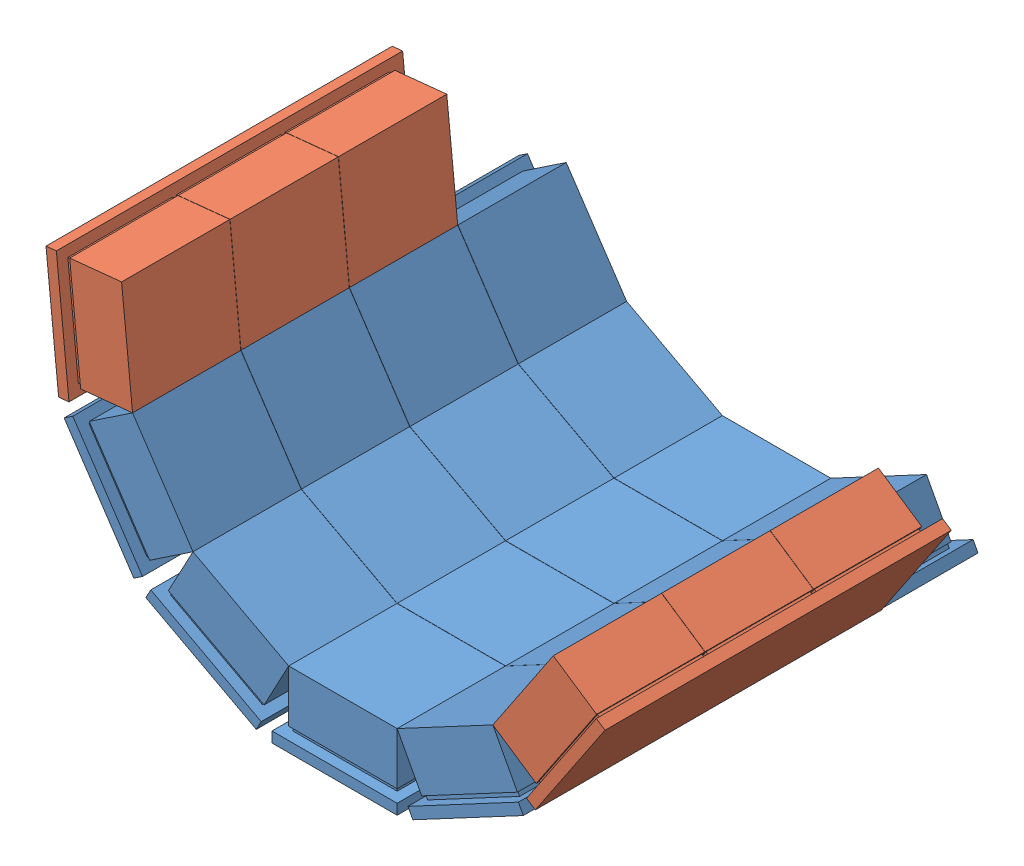
SolidWorks assembly Assem1, configuration Default. Lengths in mm.
Overall size (268 155.36 218).
6 component instances, 2 part files, 15 mates.
Components (placement in the parent):
- 52mmX4-1: 52mmX4 [Default] at (-99.1405 6.5957 36.9639) size (60 32 218)
- 52mmX4-2: 52mmX4 [Default] at (-35.1412 22.594 36.9639) x (0.882373 0.47055 0) z (0 0 1) size (60 32 218)
- 52mmX4-3: 52mmX4 [Default] at (-163.1399 22.594 36.9639) x (0.882373 -0.47055 0) z (0 0 1) size (60 32 218)
- 52mmX4-4: 52mmX4 [Default] at (-212.0831 66.8254 36.9639) x (0.557166 -0.830401 0) z (0 0 1) size (60 32 218)
- 52mmX3-1: 52mmX3 [Default] at (-234.4563 128.8843 62.9639) x (0.100883 -0.994898 0) z (0 0 1) size (60 32 166)
- 52mmX3-2: 52mmX3 [Default] at (13.802 66.8254 62.9639) x (0.557166 0.830401 0) z (0 0 1) size (60 32 166)
Mates (geometry in assembly coordinates):
- Coincident1: coincident anti-aligned: line of 52mmX4-3 through (-171.024 63.0643 90.0639) axis (0 0 1); line of 52mmX4-4 through (-171.024 63.0643 141.9639) axis (0 0 -1)
- Coincident2: coincident: point of 52mmX4-3; point of 52mmX4-4
- Angle1: planar angle = 3.631507 rad anti-aligned: line of 52mmX4-4 through (-199.9966 106.2452 141.9639) axis (0.557166 -0.830401 0); line of 52mmX4-3 through (-171.024 63.0643 141.9639) axis (0.882373 -0.47055 0)
- Coincident4: coincident anti-aligned: line of 52mmX4-1 through (-125.1405 38.5957 90.0639) axis (0 0 1); line of 52mmX4-3 through (-125.1405 38.5957 141.9639) axis (0 0 -1)
- Coincident5: coincident: point of 52mmX4-1; point of 52mmX4-3
- Angle2: planar angle = 3.631507 rad anti-aligned: line of 52mmX4-3 through (-171.024 63.0643 141.9639) axis (0.882373 -0.47055 0); line of 52mmX4-1 through (-125.1405 38.5957 141.9639) axis (1 0 0)
- Coincident7: coincident: line of 52mmX4-1 through (-73.1405 38.5957 141.9639) axis (0 0 -1); line of 52mmX4-2 through (-73.1405 38.5957 90.0639) axis (0 0 1)
- Coincident8: coincident: point of 52mmX4-1; point of 52mmX4-2
- Angle3: planar angle = 3.631507 rad anti-aligned: line of 52mmX4-1 through (-125.1405 38.5957 141.9639) axis (1 0 0); line of 52mmX4-2 through (-73.1405 38.5957 141.9639) axis (0.882373 0.47055 0)
- Coincident10: coincident: line of 52mmX4-4 through (-199.9966 106.2452 90.0639) axis (0 0 1); line of 52mmX3-1 through (-199.9966 106.2452 141.9639) axis (0 0 -1)
- Angle4: planar angle = 3.631507 rad: line of 52mmX3-1 through (-205.2425 157.9799 141.9639) axis (0.100883 -0.994898 0); line of 52mmX4-4 through (-199.9966 106.2452 141.9639) axis (0.557166 -0.830401 0)
- Coincident12: coincident: point of 52mmX4-4; point of 52mmX3-1
- Coincident13: coincident: line of 52mmX4-2 through (-27.2571 63.0643 141.9639) axis (0 0 -1); line of 52mmX3-2 through (-27.2571 63.0643 90.0639) axis (0 0 1)
- Angle5: planar angle = 3.631507 rad: line of 52mmX3-2 through (-27.2571 63.0643 141.9639) axis (0.557166 0.830401 0); line of 52mmX4-2 through (-73.1405 38.5957 141.9639) axis (0.882373 0.47055 0)
- Coincident15: coincident: point of 52mmX4-2; point of 52mmX3-2
